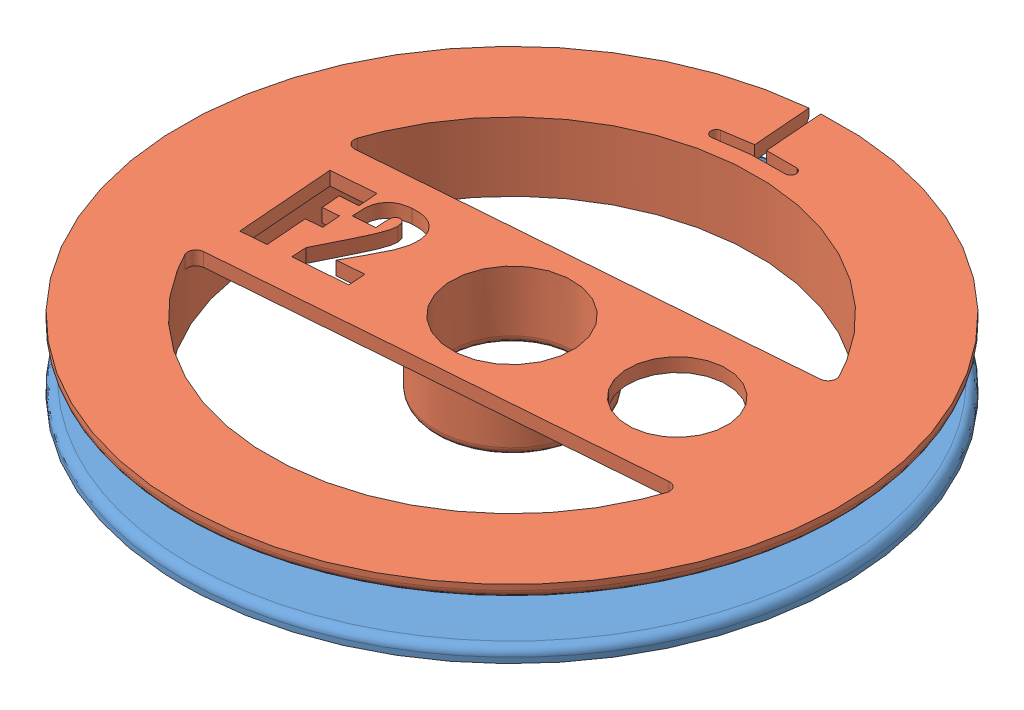
SolidWorks assembly reel_95120, configuration Predeterminado. Lengths in mm.
Overall size (128.95 12.5 129.02).
2 component instances, 2 part files, 2 mates.
Components (placement in the parent):
- reel_95120_p2-2: reel_95120_p2 [Predeterminado] at origin size (120 10 120)
- reel_95120_p1-2: reel_95120_p1 [Predeterminado] at (0 12.5 0) x (-0.996986 0 0.077577) z (0.077577 0 0.996986) size (120 12.5 120.08)
Mates (geometry in assembly coordinates):
- Concéntrica1: concentric: cylinder of reel_95120_p2-2 through (0 2.5 0) axis (0 -1 0) radius 46; cylinder of reel_95120_p1-2 through (0 0 0) axis (0 1 0) radius 45.75
- Coincidente1: coincident: plane of reel_95120_p2-2 through (0 0 0) normal (0 -1 0); plane of reel_95120_p1-2 through (0 0 0) normal (0 -1 0)
